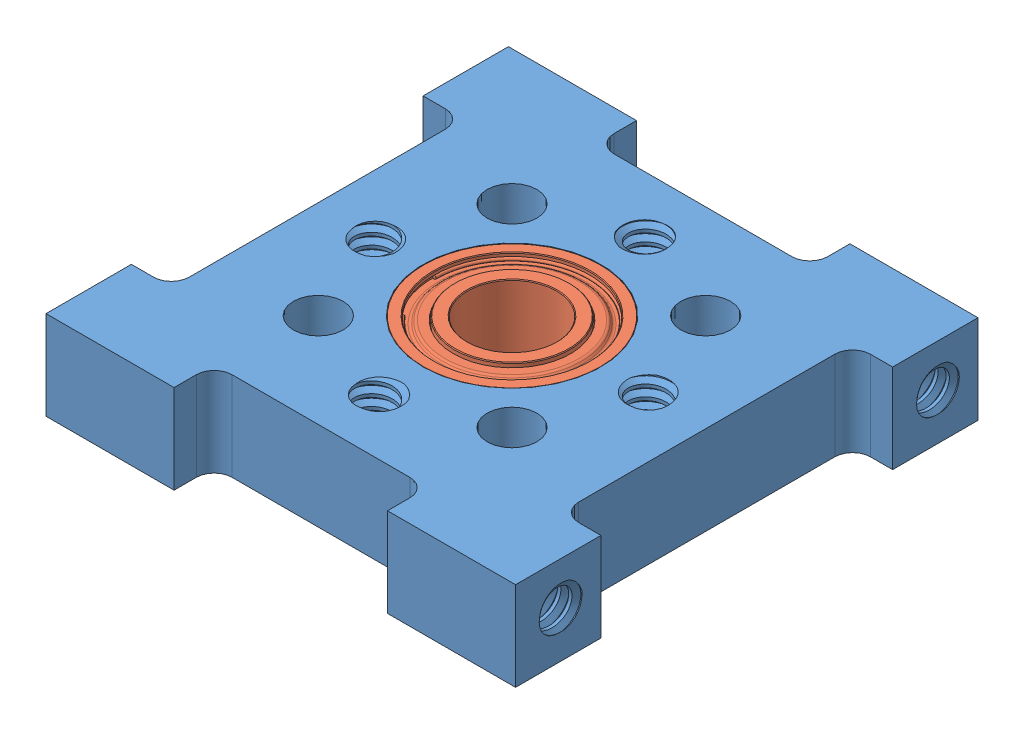
SolidWorks assembly 535130 assembly, configuration Default. Lengths in mm.
Overall size (33.73 6.55 33.02).
2 component instances, 2 part files, 0 mates.
Components (placement in the parent):
- 535130-1: 535130 [Default] at (7.6184 14.2154 28.3917) size (33.73 6.55 33.02)
- 535020-1: 535020 [Default] at (7.6184 18.1715 28.3917) size (12.7 4.76 12.7)
